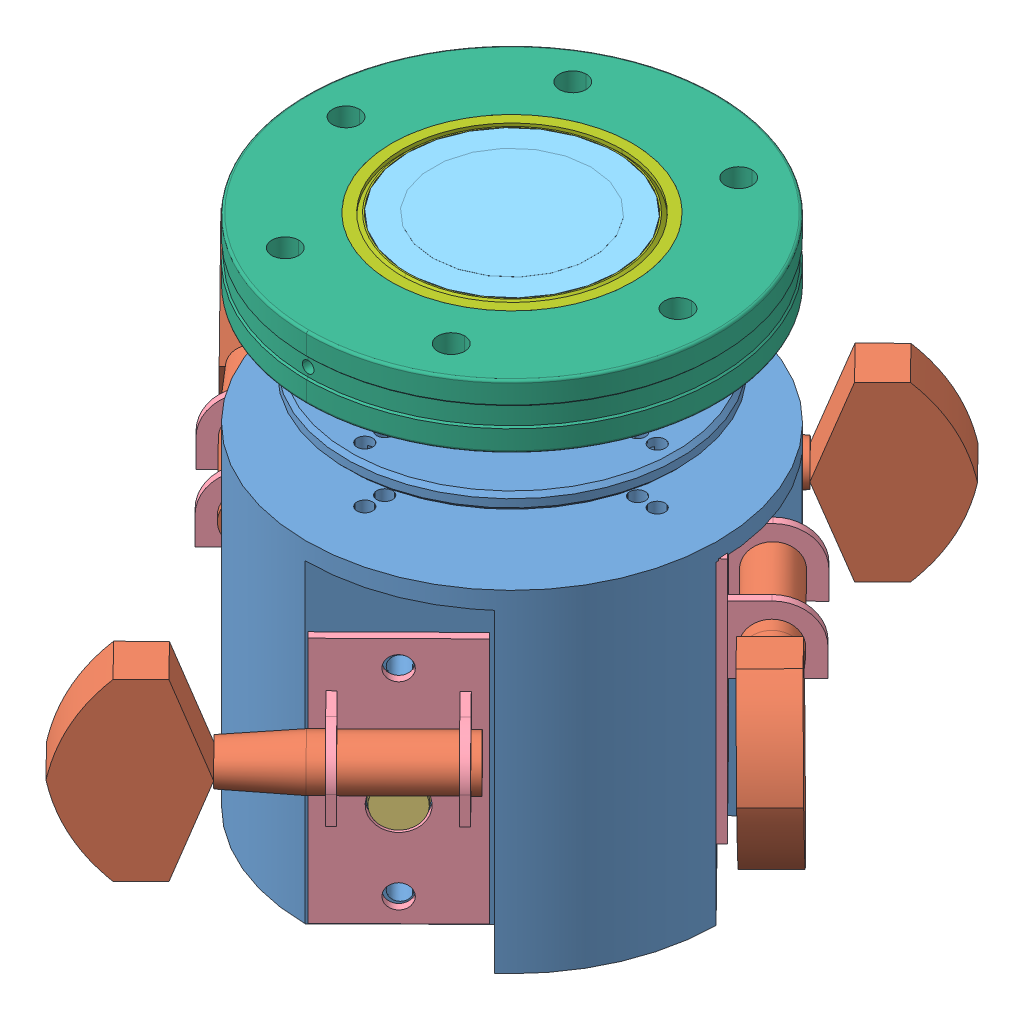
SolidWorks assembly base_link, configuration 默认. Lengths in mm.
Overall size (98.79 106.88 98.79).
68 component instances, 19 part files, 5 mates.
Components (placement in the parent):
- Shoulder_Joint_Fix_L_ASS-1: Shoulder_Joint_Fix_L_ASS [默认] at (-8.5883 9.1785 14) size (80 71.53 44) (hidden)
  - Shoulder_Joint_Fix_L-1: Shoulder_Joint_Fix_L [默认] at (-2.8963 -28.6407 70) size (80 53 44)
  - Shoulder_Joint_Fix_BC_L-2: Shoulder_Joint_Fix_BC_L [默认] at (-25.8963 -28.6407 70) x (0 0 1) z (1 0 0) size (28 15 16)
  - Shoulder_Joint_Fix_Pulley_3_10_4-1: Shoulder_Joint_Fix_Pulley_3_10_4 [默认] at (-30.8963 -40.6407 88) x (-0.923728 -0.383049 0) z (0.383049 -0.923728 0) size (10 4 10)
  - Shoulder_Joint_Fix_Pulley_3_10_4-2: Shoulder_Joint_Fix_Pulley_3_10_4 [默认] at (-30.8963 -40.6407 56) x (-0.923728 -0.383049 0) z (0.383049 -0.923728 0) size (10 4 10)
  - Shoulder_Joint_Fix_Axis_3_38-1: Shoulder_Joint_Fix_Axis_3_38 [默认] at (-30.8963 -40.6407 70) x (0 0 1) z (0.923728 0.383049 0) size (38 3 3)
- Shoulder_Joint_AX_basement_square-1: Shoulder_Joint_AX_basement_square [默认] at (3.5154 -19.4621 84) x (1 0 0) z (0 0 -1) size (44 5.5 44) (hidden)
- Shoulder_Joint_Fix_CON_guitar_ASS-1: Shoulder_Joint_Fix_CON_guitar_ASS [默认] at (-30.8549 -102.8513 87.961) x (0.000898 0 1) z (1 0 -0.000898) size (98.7 99.87 98.7)
  - Elbow_Basement_con_guitar_THK20-1: Elbow_Basement_con_guitar_THK20 [默认] at (-3.9161 -11.8892 50) size (50 32 50) (hidden)
  - Shoulder_Basement-1: Shoulder_Basement [默认] at (-3.9161 -21.8892 50) x (0 0 1) z (-1 0 0) size (50.5 10 50) (hidden)
  - Double_Gear_V1_2_160818-1: Double_Gear_V1_2_160818 [默认] at (-3.9161 -69.6739 50) x (0 1 0) z (0.007808 0 0.99997) size (58.22 52 52)
  - jinxianqiR-1: jinxianqiR [默认] at (3.9984 12.5824 82.2007) x (0 1 0) z (0 0 1) size (31.53 39.62 38.2) (hidden)
    - dazhou-1: dazhou [默认] at (-12.0982 1.8538 -2.2007) x (0 -1 0) z (-0.008705 0 0.999962) size (39 22 6)
    - zhou_V1_2_160817-1: zhou_V1_2_160817 [默认] at (-4.5982 0 -14.0107) x (0 0 -1) z (1 0 0) size (29.2 12.39 5.8)
    - jinxianqiR_d2_160817-2: jinxianqiR_d2_160817 [默认] at (-4.5982 0 -7.2007) size (31.25 16.25 10)
  - jinxianqiR-5: jinxianqiR [默认] at (-14.733 -38.0411 75.2549) x (0 1 0) z (-0.701564 0 0.712606) size (31.53 39.62 38.2)
    - dazhou-1: dazhou [默认] at (-12.0982 1.8538 -2.2007) x (0 -1 0) z (-0.008705 0 0.999962) size (39 22 6)
    - zhou_V1_2_160817-1: zhou_V1_2_160817 [默认] at (-4.5982 0 -14.0107) x (0 0 -1) z (1 0 0) size (29.2 12.39 5.8)
    - jinxianqiR_d2_160817-2: jinxianqiR_d2_160817 [默认] at (-4.5982 0 -7.2007) size (31.25 16.25 10)
  - jinxianqiR-6: jinxianqiR [默认] at (6.9007 -38.0411 24.7451) x (0 1 0) z (0.701564 0 -0.712606) size (31.53 39.62 38.2)
    - dazhou-1: dazhou [默认] at (-12.0982 1.8538 -2.2007) x (0 -1 0) z (-0.008705 0 0.999962) size (39 22 6)
    - zhou_V1_2_160817-1: zhou_V1_2_160817 [默认] at (-4.5982 0 -14.0107) x (0 0 -1) z (1 0 0) size (29.2 12.39 5.8)
    - jinxianqiR_d2_160817-2: jinxianqiR_d2_160817 [默认] at (-4.5982 0 -7.2007) size (31.25 16.25 10)
  - jinxianqiR-9: jinxianqiR [默认] at (21.3388 -30.0411 60.8169) x (0 1 0) z (0.712606 0 0.701564) size (31.53 39.62 38.2)
    - dazhou-1: dazhou [默认] at (-12.0982 1.8538 -2.2007) x (0 -1 0) z (-0.008705 0 0.999962) size (39 22 6)
    - zhou_V1_2_160817-1: zhou_V1_2_160817 [默认] at (-4.5982 0 -14.0107) x (0 0 -1) z (1 0 0) size (29.2 12.39 5.8)
    - jinxianqiR_d2_160817-2: jinxianqiR_d2_160817 [默认] at (-4.5982 0 -7.2007) size (31.25 16.25 10)
  - jinxianqiR-10: jinxianqiR [默认] at (-29.171 -30.0411 39.1831) x (0 1 0) z (-0.712606 0 -0.701564) size (31.53 39.62 38.2)
    - dazhou-1: dazhou [默认] at (-12.0982 1.8538 -2.2007) x (0 -1 0) z (-0.008705 0 0.999962) size (39 22 6)
    - zhou_V1_2_160817-1: zhou_V1_2_160817 [默认] at (-4.5982 0 -14.0107) x (0 0 -1) z (1 0 0) size (29.2 12.39 5.8)
    - jinxianqiR_d2_160817-2: jinxianqiR_d2_160817 [默认] at (-4.5982 0 -7.2007) size (31.25 16.25 10)
- CRBF108ATUU-2: CRBF108ATUU [Default] at (19.1415 -16.9621 84) x (0 -1 0) z (0 0 -1) size (40 52 52)
  - _CRBF108ATUU_PART1-1: _CRBF108ATUU_PART1 [Default] at origin size (40 26.4 26.4)
  - _CRBF108ATUU_PART2-1: _CRBF108ATUU_PART2 [Default] at origin size (8 52 52)
  - _CRBF108ATUU_PART3-1: _CRBF108ATUU_PART3 [Default] at origin size (1.2 30.44 30.44)
  - _CRBF108ATUU_PART4-1: _CRBF108ATUU_PART4 [Default] at origin size (1.2 30.44 30.44)
  - _CRBF108ATUU_PART5-5: _CRBF108ATUU_PART5 [Default] at origin size (4.53 4.53 3.2)
  - _CRBF108ATUU_PART5-2: _CRBF108ATUU_PART5 [Default] x (1 0 0) z (0 0.707107 0.707107) size (4.53 4.53 3.2)
  - _CRBF108ATUU_PART5-7: _CRBF108ATUU_PART5 [Default] x (1 0 0) z (0 1 0) size (4.53 4.53 3.2)
  - _CRBF108ATUU_PART5-4: _CRBF108ATUU_PART5 [Default] x (1 0 0) z (0 0.707107 -0.707107) size (4.53 4.53 3.2)
  - _CRBF108ATUU_PART5-1: _CRBF108ATUU_PART5 [Default] x (1 0 0) z (0 0 -1) size (4.53 4.53 3.2)
  - _CRBF108ATUU_PART5-6: _CRBF108ATUU_PART5 [Default] x (1 0 0) z (0 -0.707107 -0.707107) size (4.53 4.53 3.2)
  - _CRBF108ATUU_PART5-8: _CRBF108ATUU_PART5 [Default] x (1 0 0) z (0 -1 0) size (4.53 4.53 3.2)
  - _CRBF108ATUU_PART5-3: _CRBF108ATUU_PART5 [Default] x (1 0 0) z (0 -0.707107 0.707107) size (4.53 4.53 3.2)
  - _CRBF108ATUU_PART6-6: _CRBF108ATUU_PART6 [Default] at origin size (4.43 4.44 3.71)
  - _CRBF108ATUU_PART6-1: _CRBF108ATUU_PART6 [Default] x (1 0 0) z (0 0.707107 0.707107) size (4.43 4.44 3.71)
  - _CRBF108ATUU_PART6-5: _CRBF108ATUU_PART6 [Default] x (1 0 0) z (0 1 0) size (4.43 4.44 3.71)
  - _CRBF108ATUU_PART6-7: _CRBF108ATUU_PART6 [Default] x (1 0 0) z (0 0.707107 -0.707107) size (4.43 4.44 3.71)
  - _CRBF108ATUU_PART6-4: _CRBF108ATUU_PART6 [Default] x (1 0 0) z (0 0 -1) size (4.43 4.44 3.71)
  - _CRBF108ATUU_PART6-8: _CRBF108ATUU_PART6 [Default] x (1 0 0) z (0 -0.707107 -0.707107) size (4.43 4.44 3.71)
  - _CRBF108ATUU_PART6-2: _CRBF108ATUU_PART6 [Default] x (1 0 0) z (0 -1 0) size (4.43 4.44 3.71)
  - _CRBF108ATUU_PART6-3: _CRBF108ATUU_PART6 [Default] x (1 0 0) z (0 -0.707107 0.707107) size (4.43 4.44 3.71)
  - _CRBF108ATUU_PART7-4: _CRBF108ATUU_PART7 [Default] at origin size (2.6 2.78 1.68)
  - _CRBF108ATUU_PART7-8: _CRBF108ATUU_PART7 [Default] x (1 0 0) z (0 0.707107 0.707107) size (2.6 2.78 1.68)
  - _CRBF108ATUU_PART7-3: _CRBF108ATUU_PART7 [Default] x (1 0 0) z (0 1 0) size (2.6 2.78 1.68)
  - _CRBF108ATUU_PART7-5: _CRBF108ATUU_PART7 [Default] x (1 0 0) z (0 0.707107 -0.707107) size (2.6 2.78 1.68)
  - _CRBF108ATUU_PART7-7: _CRBF108ATUU_PART7 [Default] x (1 0 0) z (0 0 -1) size (2.6 2.78 1.68)
  - _CRBF108ATUU_PART7-2: _CRBF108ATUU_PART7 [Default] x (1 0 0) z (0 -0.707107 -0.707107) size (2.6 2.78 1.68)
  - _CRBF108ATUU_PART7-1: _CRBF108ATUU_PART7 [Default] x (1 0 0) z (0 -1 0) size (2.6 2.78 1.68)
  - _CRBF108ATUU_PART7-6: _CRBF108ATUU_PART7 [Default] x (1 0 0) z (0 -0.707107 0.707107) size (2.6 2.78 1.68)
  - _CRBF108ATUU_PART8-4: _CRBF108ATUU_PART8 [Default] at origin size (2.6 2.83 2.44)
  - _CRBF108ATUU_PART8-8: _CRBF108ATUU_PART8 [Default] x (1 0 0) z (0 0.707107 0.707107) size (2.6 2.83 2.44)
  - _CRBF108ATUU_PART8-6: _CRBF108ATUU_PART8 [Default] x (1 0 0) z (0 1 0) size (2.6 2.83 2.44)
  - _CRBF108ATUU_PART8-7: _CRBF108ATUU_PART8 [Default] x (1 0 0) z (0 0.707107 -0.707107) size (2.6 2.83 2.44)
  - _CRBF108ATUU_PART8-5: _CRBF108ATUU_PART8 [Default] x (1 0 0) z (0 0 -1) size (2.6 2.83 2.44)
  - _CRBF108ATUU_PART8-2: _CRBF108ATUU_PART8 [Default] x (1 0 0) z (0 -0.707107 -0.707107) size (2.6 2.83 2.44)
  - _CRBF108ATUU_PART8-1: _CRBF108ATUU_PART8 [Default] x (1 0 0) z (0 -1 0) size (2.6 2.83 2.44)
  - _CRBF108ATUU_PART8-3: _CRBF108ATUU_PART8 [Default] x (1 0 0) z (0 -0.707107 0.707107) size (2.6 2.83 2.44)
Mates (geometry in assembly coordinates):
- 同心10: concentric anti-aligned: cylinder of Shoulder_Joint_Fix_L_ASS-1/Shoulder_Joint_Fix_L-1 through (3.5154 -16.4621 84) axis (0 -1 0) radius 13.75; cylinder of Shoulder_Joint_AX_basement_square-1 through (3.5154 -26.4621 84) axis (0 1 0) radius 9
- 重合14: coincident anti-aligned: plane of Shoulder_Joint_Fix_L_ASS-1/Shoulder_Joint_Fix_L-1 through (-11.4846 -19.4621 84) normal (0 -1 0); plane of Shoulder_Joint_AX_basement_square-1 through (3.5154 -19.4621 84) normal (0 1 0)
- 重合15: coincident aligned: plane of Shoulder_Joint_Fix_L_ASS-1/Shoulder_Joint_Fix_L-1 through (-51.4846 -16.4621 106) normal (0 0 1); plane of Shoulder_Joint_AX_basement_square-1 through (-18.4846 -24.9621 106) normal (0 0 1)
- 同心26: concentric anti-aligned: cylinder of Shoulder_Joint_Fix_CON_guitar_ASS-1/Double_Gear_V1_2_160818-1 through (19.1415 -23.9621 84) axis (0 -1 0) radius 5; cylinder of CRBF108ATUU-2/_CRBF108ATUU_PART1-1 through (19.1415 -24.9621 84) axis (0 1 0) radius 5
- 距离10: distance = 1 mm anti-aligned: plane of Shoulder_Joint_Fix_CON_guitar_ASS-1/Double_Gear_V1_2_160818-1 through (19.1415 -23.9621 84) normal (0 1 0); plane of CRBF108ATUU-2/_CRBF108ATUU_PART2-1 through (3.9215 -24.9621 84) normal (0 -1 0)
